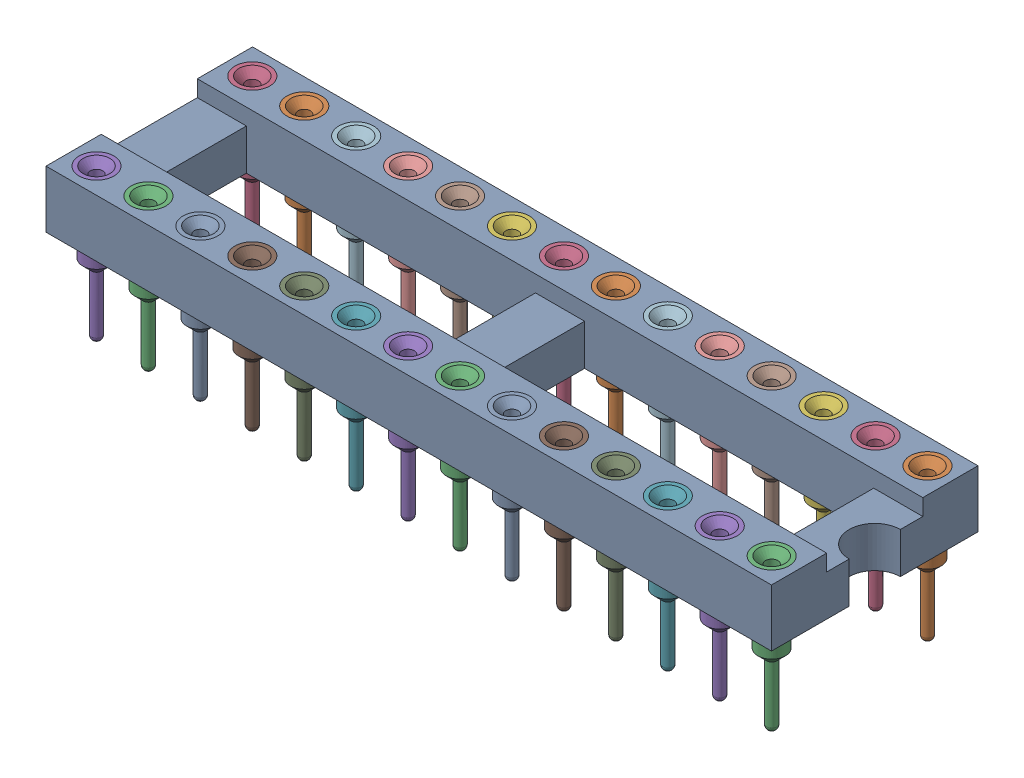
SolidWorks assembly dip28, configuration Default. Lengths in mm.
Overall size (35.48 7.37 10.1).
29 component instances, 2 part files, 0 mates.
Components (placement in the parent):
- dip28-1: dip28 [Default] at origin size (35.48 2.8 10.1)
- dip socket pin-1: dip socket pin [Default] at (16.51 2.8 -3.81) size (1.7 7.37 1.7)
- dip socket pin-2: dip socket pin [Default] at (16.51 2.8 3.81) size (1.7 7.37 1.7)
- dip socket pin-3: dip socket pin [Default] at (13.97 2.8 -3.81) size (1.7 7.37 1.7)
- dip socket pin-4: dip socket pin [Default] at (13.97 2.8 3.81) size (1.7 7.37 1.7)
- dip socket pin-5: dip socket pin [Default] at (11.43 2.8 -3.81) size (1.7 7.37 1.7)
- dip socket pin-6: dip socket pin [Default] at (11.43 2.8 3.81) size (1.7 7.37 1.7)
- dip socket pin-7: dip socket pin [Default] at (8.89 2.8 -3.81) size (1.7 7.37 1.7)
- dip socket pin-8: dip socket pin [Default] at (8.89 2.8 3.81) size (1.7 7.37 1.7)
- dip socket pin-9: dip socket pin [Default] at (6.35 2.8 -3.81) size (1.7 7.37 1.7)
- dip socket pin-10: dip socket pin [Default] at (6.35 2.8 3.81) size (1.7 7.37 1.7)
- dip socket pin-11: dip socket pin [Default] at (3.81 2.8 -3.81) size (1.7 7.37 1.7)
- dip socket pin-12: dip socket pin [Default] at (3.81 2.8 3.81) size (1.7 7.37 1.7)
- dip socket pin-13: dip socket pin [Default] at (1.27 2.8 -3.81) size (1.7 7.37 1.7)
- dip socket pin-14: dip socket pin [Default] at (1.27 2.8 3.81) size (1.7 7.37 1.7)
- dip socket pin-15: dip socket pin [Default] at (-1.27 2.8 -3.81) size (1.7 7.37 1.7)
- dip socket pin-16: dip socket pin [Default] at (-1.27 2.8 3.81) size (1.7 7.37 1.7)
- dip socket pin-17: dip socket pin [Default] at (-3.81 2.8 -3.81) size (1.7 7.37 1.7)
- dip socket pin-18: dip socket pin [Default] at (-3.81 2.8 3.81) size (1.7 7.37 1.7)
- dip socket pin-19: dip socket pin [Default] at (-6.35 2.8 -3.81) size (1.7 7.37 1.7)
- dip socket pin-20: dip socket pin [Default] at (-6.35 2.8 3.81) size (1.7 7.37 1.7)
- dip socket pin-21: dip socket pin [Default] at (-8.89 2.8 -3.81) size (1.7 7.37 1.7)
- dip socket pin-22: dip socket pin [Default] at (-8.89 2.8 3.81) size (1.7 7.37 1.7)
- dip socket pin-23: dip socket pin [Default] at (-11.43 2.8 -3.81) size (1.7 7.37 1.7)
- dip socket pin-24: dip socket pin [Default] at (-11.43 2.8 3.81) size (1.7 7.37 1.7)
- dip socket pin-25: dip socket pin [Default] at (-13.97 2.8 -3.81) size (1.7 7.37 1.7)
- dip socket pin-26: dip socket pin [Default] at (-13.97 2.8 3.81) size (1.7 7.37 1.7)
- dip socket pin-27: dip socket pin [Default] at (-16.51 2.8 -3.81) size (1.7 7.37 1.7)
- dip socket pin-28: dip socket pin [Default] at (-16.51 2.8 3.81) size (1.7 7.37 1.7)
